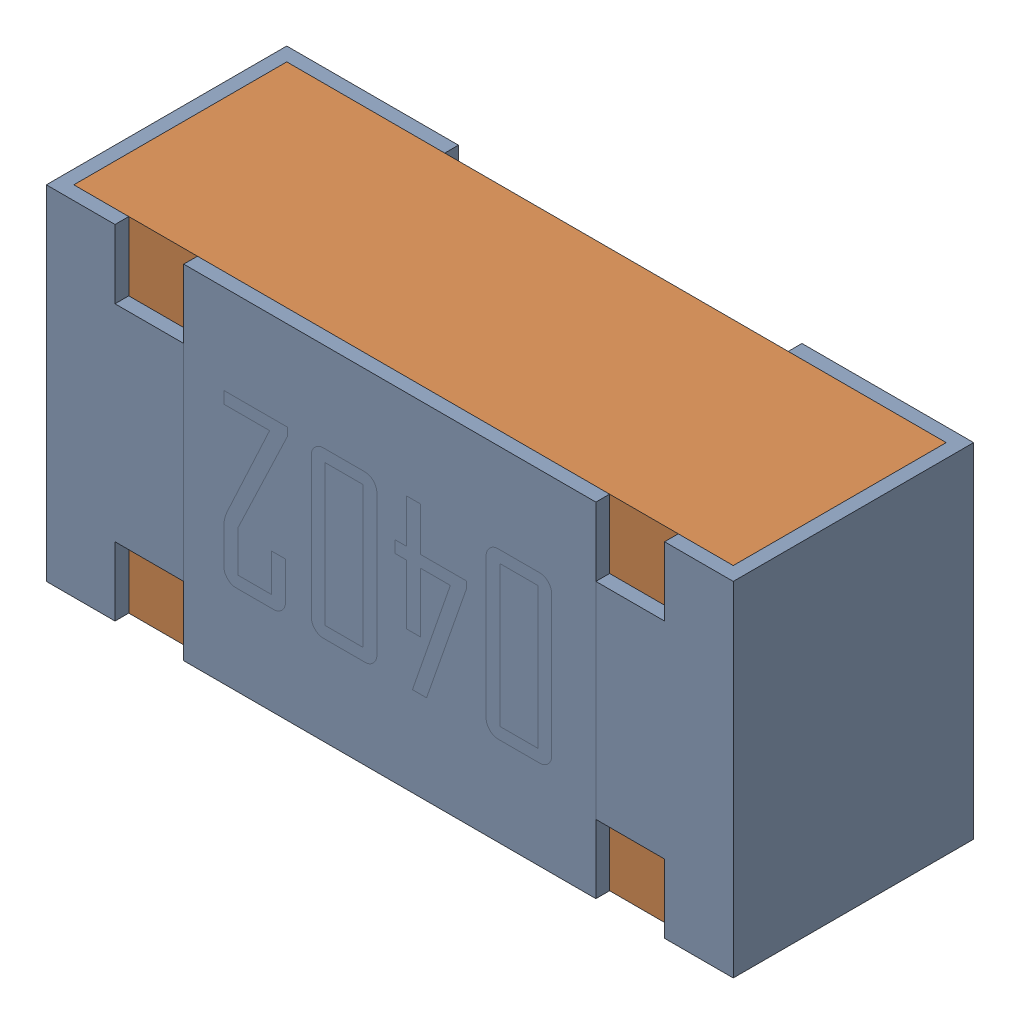
SolidWorks assembly R3, configuration Default. Lengths in mm.
Overall size (1 0.5 0.35).
3 component instances, 2 part files, 0 mates.
Components (placement in the parent):
- R3-subassembly-1-1: R3-subassembly-1 [Default] at (-15.4999 1.5 0) x (-1 0 0) z (0 1 0) size (1 0.35 0.5)
  - 0402 resistor-1: 0402 resistor [Default] at origin size (1 0.35 0.5)
  - 0402 resistor-1-1: 0402 resistor-1 [Default] at origin size (0.96 0.31 0.5)
